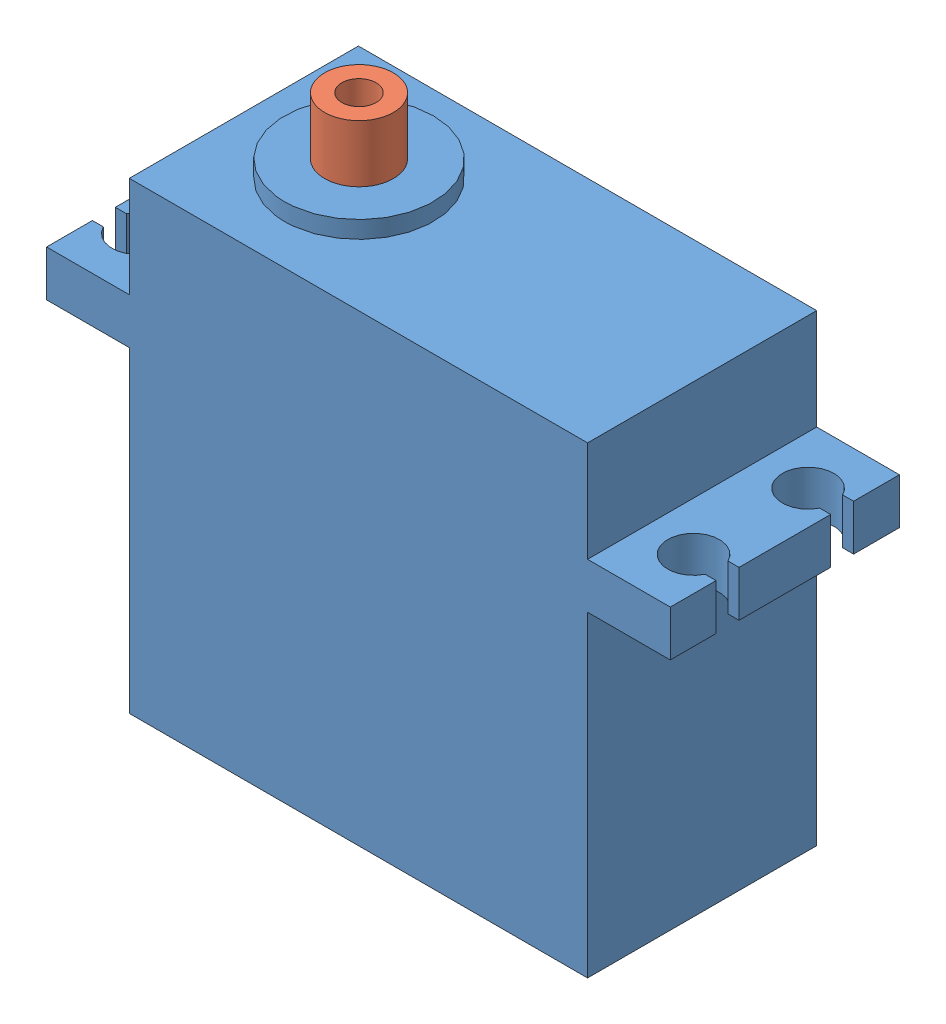
SolidWorks assembly 20KGServo, configuration Default. Lengths in mm.
Overall size (54.44 46.95 20).
2 component instances, 2 part files, 2 mates.
Components (placement in the parent):
- 20KGServoBase-1: 20KGServoBase [Default] at origin size (54.44 41.95 20)
- 20KGServoShaft-1: 20KGServoShaft [Default] at (-9.95 41.95 0) x (0.780232 0 -0.62549) z (0.62549 0 0.780232) size (6 5 6)
Mates (geometry in assembly coordinates):
- Coincident1: coincident anti-aligned: plane of ServoBase-1 through (0 41.95 0) normal (0 1 0); plane of servo_shaft-1 through (-9.95 41.95 0) normal (0 -1 0)
- Concentric1: concentric aligned: circle of servo_base-1; circle of servo_shaft-1
